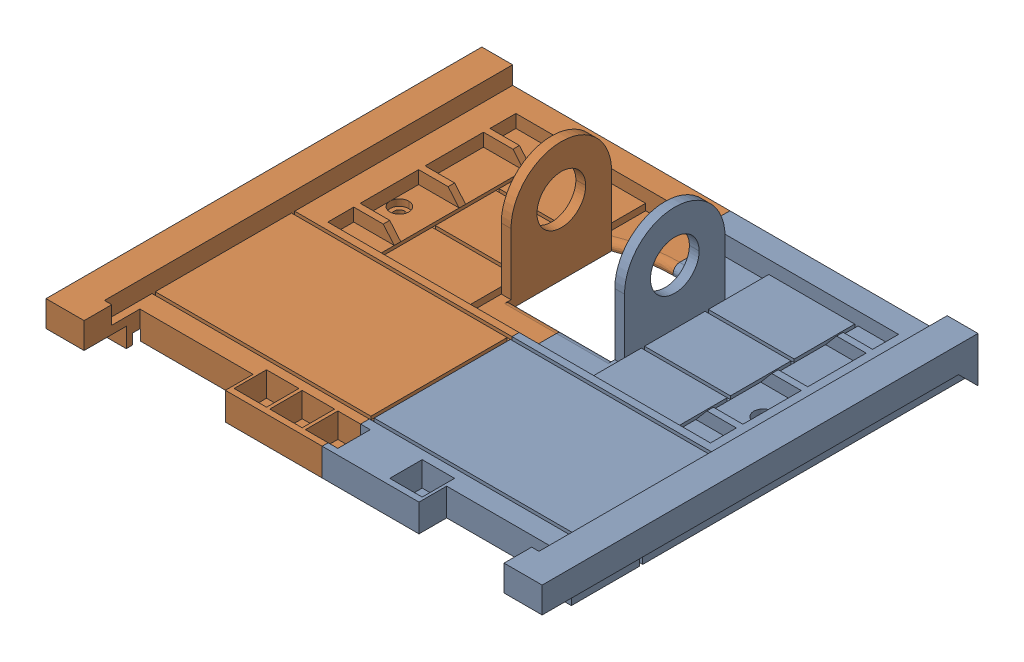
SolidWorks assembly body-top-split, configuration Default. Lengths in mm.
Overall size (255 61.67 224).
2 component instances, 2 part files, 2 mates.
Components (placement in the parent):
- body-top-left-1: body-top-left [Default] at (-105.7234 -16.895 67.267) size (127.5 61.67 224)
- body-top-right-1: body-top-right [Default] at (-105.7234 -16.895 67.267) size (127.5 61.67 224)
Mates (geometry in assembly coordinates):
- Coincident1: coincident: plane of body-top-left-1 through (-29.1845 -16.895 67.267) normal (-1 0 0); plane of body-top-right-1 through (-29.1845 -15.7876 74.8544) normal (1 0 0)
- Coincident2: coincident anti-aligned: circle of body-top-left-1; circle of body-top-right-1
